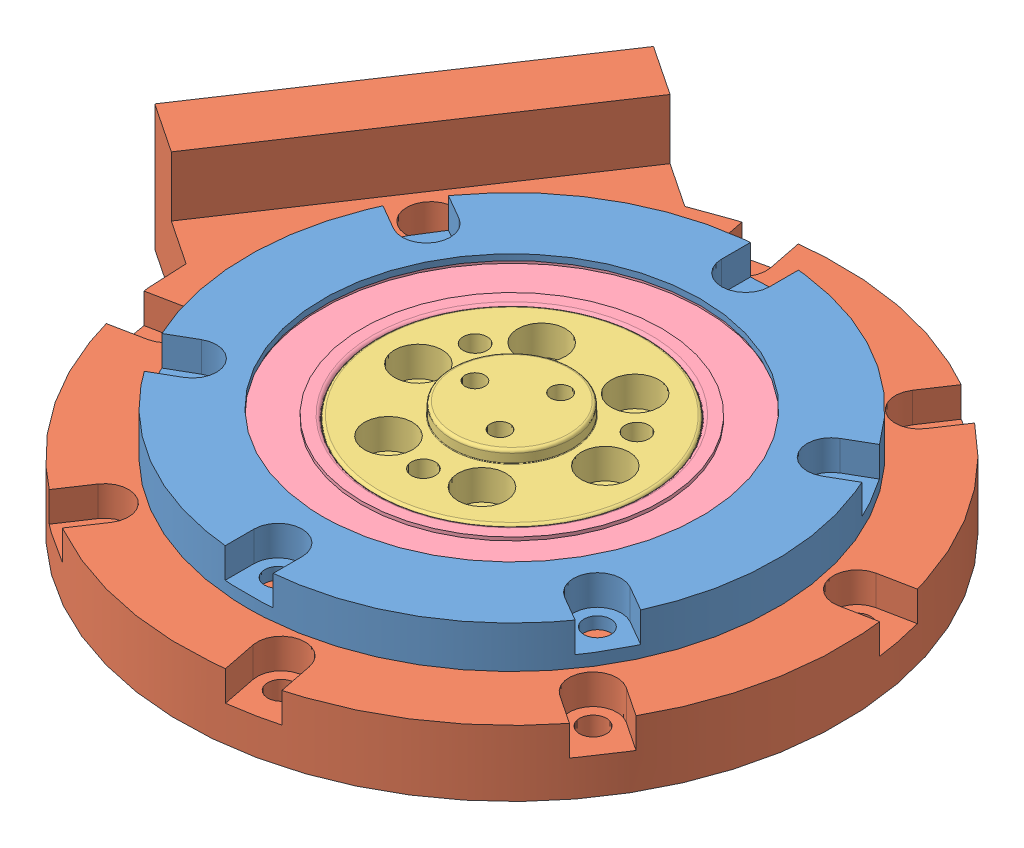
SolidWorks assembly Knee Assemble v2, configuration 기본. Lengths in mm.
Overall size (160.88 21 158.11).
4 component instances, 4 part files, 13 mates.
Components (placement in the parent):
- Actuator Jig Bearing Cap v2-1: Actuator Jig Bearing Cap v2 [기본] at (-1.6384 1.051 88) size (88 7 88)
- Actuator Jig v2-1: Actuator Jig v2 [기본] at (-1.6384 -9.949 88) x (0.831699 0 0.555227) z (-0.555227 0 0.831699) size (120 21 110)
- Load Flange v2-1: Load Flange v2 [기본] at (-1.6384 -9.949 88) x (-0.027558 0 -0.99962) z (0.99962 0 -0.027558) size (50 17 50)
- C-SE6909ZZ.stp-1: C-SE6909ZZ.stp [기본] at (-1.6384 -4.949 88) x (0 1 0) z (-0.818577 0 0.574397) size (12 68 68)
Mates (geometry in assembly coordinates):
- 동심1: concentric aligned: circle of Actuator Jig Bearing Cap v2-1; circle of Actuator Jig v2-1
- 동심2: concentric anti-aligned: circle of Actuator Jig v2-1; circle of NSK_7909A5-1/7909A5 Outer ring-1
- 일치4: coincident anti-aligned: plane of Actuator Jig v2-1 through (-1.6384 -4.949 88) normal (0 1 0); plane of NSK_7909A5-1/7909A5 Outer ring-1 through (15.4759 -4.949 61.2574) normal (0 -1 0)
- 일치6: coincident anti-aligned: plane of Actuator Jig Bearing Cap v2-1 through (-1.6384 7.051 88) normal (0 -1 0); plane of NSK_7909A5-1/7909A5 Outer ring-1 through (16.3653 7.051 59.8677) normal (0 1 0)
- 동심3: concentric anti-aligned: circle of Load Flange v2-1; circle of NSK_7909A5-1/7909A5 Inner ring-1
- 일치7: coincident anti-aligned: plane of Load Flange v2-1 through (-1.6384 -4.949 88) normal (0 1 0); plane of NSK_7909A5-1/7909A5 Inner ring-1 through (10.8132 -4.949 68.5432) normal (0 -1 0)
- 동심4: concentric anti-aligned: circle of NSK_7909A5-1/7909A5 Inner ring-1; circle of Knee Link v2-1
- 동심7: concentric aligned: circle of Load Flange v2-1; circle of Knee Link v2-1
- 동심8: concentric aligned: circle of Actuator Jig Bearing Cap v2-1; circle of C-SE6909ZZ.stp-1
- 동심10: concentric aligned: circle of Load Flange v2-1; circle of C-SE6909ZZ.stp-1
- 일치11: coincident anti-aligned: plane of Load Flange v2-1 through (-1.6384 -4.949 88) normal (0 1 0); plane of C-SE6909ZZ.stp-1 through (-15.9983 -4.949 67.5356) normal (0 -1 0)
- 일치12: coincident anti-aligned: plane of Actuator Jig v2-1 through (-1.6384 -4.949 88) normal (0 1 0); plane of C-SE6909ZZ.stp-1 through (-20.8232 -4.949 60.6595) normal (0 -1 0)
- 일치13: coincident anti-aligned: plane of Actuator Jig Bearing Cap v2-1 through (-1.6384 7.051 88) normal (0 -1 0); plane of C-SE6909ZZ.stp-1 through (-19.8755 7.051 62.0102) normal (0 1 0)
